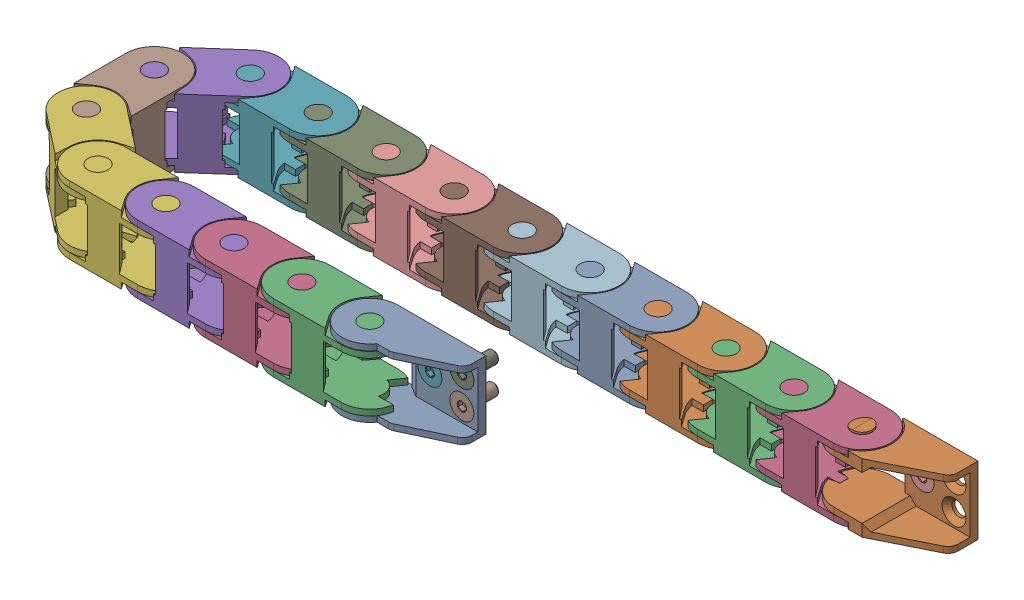
SolidWorks assembly 10x11 Chain X, configuration Default. Lengths in mm.
Overall size (197.76 18 61.73).
22 component instances, 4 part files, 0 mates.
Components (placement in the parent):
- 10x11 Unfixed End v1-1: 10x11 Unfixed End v1 [Default] at (-16.215 17 36) x (-1 0 0) z (0 0 1) size (29 17 14)
- 10x11 Fixed End v1-1: 10x11 Fixed End v1 [Default] at (68.1252 17 -2.7505) x (-1 0 0) z (0 0 1) size (28.83 18 14)
- 10x11 Chain Link v1-1: 10x11 Chain Link v1 [Default] at (-33.215 15.5 36) size (31.2 17 14.3)
- 10x11 Chain Link v1-2: 10x11 Chain Link v1 [Default] at (-50.215 15.5 36) size (31.2 17 14.3)
- 10x11 Chain Link v1-3: 10x11 Chain Link v1 [Default] at (-67.215 15.5 36) size (31.2 17 14.3)
- 10x11 Chain Link v1-4: 10x11 Chain Link v1 [Default] at (-84.215 15.5 36) size (31.2 17 14.3)
- 10x11 Chain Link v1-5: 10x11 Chain Link v1 [Default] at (-67.8748 15.5 -2.7505) x (-1 0 0) z (0 0 -1) size (31.2 17 14.3)
- 10x11 Chain Link v1-6: 10x11 Chain Link v1 [Default] at (-97.5929 15.5 8.5104) x (0 0 1) z (-1 0 0) size (31.2 17 14.3)
- 10x11 Chain Link v1-7: 10x11 Chain Link v1 [Default] at (-50.8748 15.5 -2.7505) x (-1 0 0) z (0 0 -1) size (31.2 17 14.3)
- 10x11 Chain Link v1-8: 10x11 Chain Link v1 [Default] at (-33.8748 15.5 -2.7505) x (-1 0 0) z (0 0 -1) size (31.2 17 14.3)
- 10x11 Chain Link v1-9: 10x11 Chain Link v1 [Default] at (-16.8748 15.5 -2.7505) x (-1 0 0) z (0 0 -1) size (31.2 17 14.3)
- 10x11 Chain Link v1-10: 10x11 Chain Link v1 [Default] at (0.1252 15.5 -2.7505) x (-1 0 0) z (0 0 -1) size (31.2 17 14.3)
- 10x11 Chain Link v1-11: 10x11 Chain Link v1 [Default] at (17.1252 15.5 -2.7505) x (-1 0 0) z (0 0 -1) size (31.2 17 14.3)
- 10x11 Chain Link v1-12: 10x11 Chain Link v1 [Default] at (34.1252 15.5 -2.7505) x (-1 0 0) z (0 0 -1) size (31.2 17 14.3)
- 10x11 Chain Link v1-13: 10x11 Chain Link v1 [Default] at (51.1252 15.5 -2.7505) x (-1 0 0) z (0 0 -1) size (31.2 17 14.3)
- 10x11 Chain Link v1-14: 10x11 Chain Link v1 [Default] at (68.1252 15.5 -2.7505) x (-1 0 0) z (0 0 -1) size (31.2 17 14.3)
- 10x11 Chain Link v1-15: 10x11 Chain Link v1 [Default] at (-84.8748 15.5 -2.7505) x (-0.748956 0 0.66262) z (-0.66262 0 -0.748956) size (31.2 17 14.3)
- 10x11 Chain Link v1-16: 10x11 Chain Link v1 [Default] at (-97.5929 15.5 25.5104) x (0.786935 0 0.617036) z (-0.617036 0 0.786935) size (31.2 17 14.3)
- M3x8 FHCS-1: M3x8 FHCS [Default] at (-6.215 8.5 31) x (-1 0 0) z (0 0 1) size (6 6 8.12)
- M3x8 FHCS-2: M3x8 FHCS [Default] at (1.785 5 31) x (-1 0 0) z (0 0 1) size (6 6 8.12)
- M3x8 FHCS-3: M3x8 FHCS [Default] at (1.785 12 31) x (-1 0 0) z (0 0 1) size (6 6 8.12)
- M3x8 FHCS-4: M3x8 FHCS [Default] at (78.1252 8.5 -7.7505) x (-1 0 0) z (0 0 1) size (6 6 8.12)
